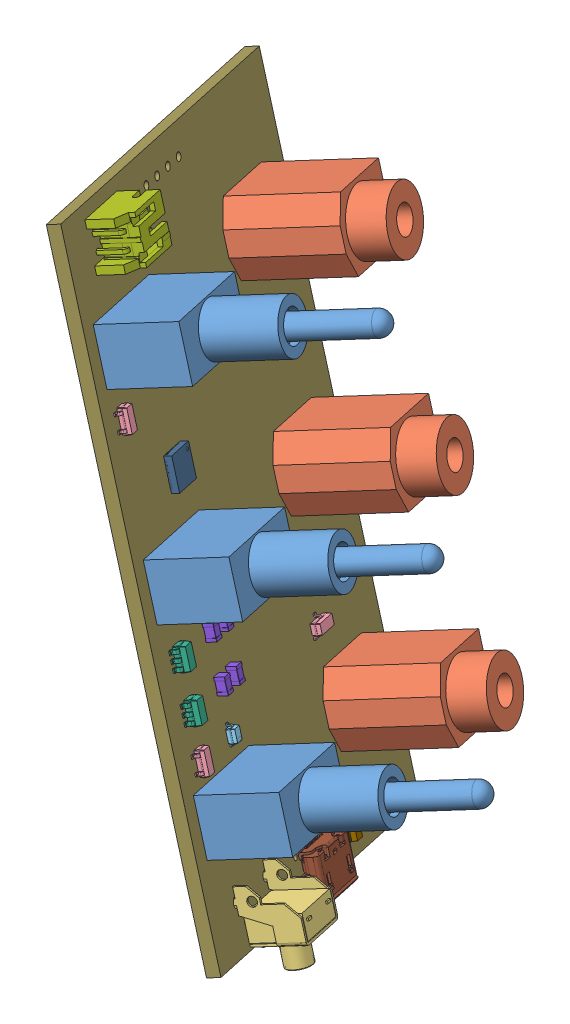
SolidWorks assembly PCB-assembly_v1.1, configuration Default. Lengths in mm.
Overall size (64.17 83.92 50.34).
100 component instances, 15 part files, 54 mates.
Components (placement in the parent):
- toggle-switch-4: toggle-switch [Default] at (-67.9927 86.0354 100.4663) x (0.334215 -0.940873 0.055309) z (0.337053 0.174117 0.925245) size (6.9 31.5 13.2)
- 3,5mmjack_MultiComp-1: 3,5mmjack_MultiComp [Default] at (-77.3391 81.8383 75.298) x (-0.334215 0.940873 -0.055309) z (0.880168 0.290588 -0.375317) size (9 10.5 21.9)
- ledTruckv1.1_new-1: ledTruckv1.1_new [Default] at (-61.225 73.4972 110.8928) x (-0.334215 0.940873 -0.055309) z (0.880168 0.290588 -0.375317) size (82.71 47 11)
  - R_0603_1608Metric-1: R_0603_1608Metric [Default] at (8.89 -22.225 1.65) x (-1 0 0) z (0 0 1) size (1.6 0.8 0.45)
    - SOLID-0-1: SOLID-0 [Default] at origin size (1.6 0.8 0.45) (hidden)
  - R_0603_1608Metric-2: R_0603_1608Metric [Default] at (8.89 -24.003 1.65) size (1.6 0.8 0.45)
    - SOLID-0-1: SOLID-0 [Default] at origin size (1.6 0.8 0.45) (hidden)
  - SW_Tactile_SPST_Angled_PTS645Vx58-2LFS-1: SW_Tactile_SPST_Angled_PTS645Vx58-2LFS [Default] at (3 -12 1.65) x (0 1 0) z (0 0 1) size (7.4 9.9 11)
    - SOLID-1-1: SOLID-1 [Default] at origin size (7.4 9.9 11)
  - R_0603_1608Metric-3: R_0603_1608Metric [Default] at (26.416 -8.636 1.65) x (-1 0 0) z (0 0 1) size (1.6 0.8 0.45)
    - SOLID-0-1: SOLID-0 [Default] at origin size (1.6 0.8 0.45) (hidden)
  - R_0603_1608Metric-4: R_0603_1608Metric [Default] at (21.082 -14.478 1.65) size (1.6 0.8 0.45)
    - SOLID-0-1: SOLID-0 [Default] at origin size (1.6 0.8 0.45) (hidden)
  - R_0603_1608Metric-5: R_0603_1608Metric [Default] at (21.082 -8.636 1.65) x (-1 0 0) z (0 0 1) size (1.6 0.8 0.45)
    - SOLID-0-1: SOLID-0 [Default] at origin size (1.6 0.8 0.45) (hidden)
  - R_0603_1608Metric-6: R_0603_1608Metric [Default] at (27.686 -35.052 1.65) x (-1 0 0) z (0 0 1) size (1.6 0.8 0.45)
    - SOLID-0-1: SOLID-0 [Default] at origin size (1.6 0.8 0.45) (hidden)
  - SOT-23-1: SOT-23 [Default] at (21.082 -4.572 1.65) x (0 -1 0) z (0 0 1) size (2.5 3 1.2)
    - SOLID-2-1: SOLID-2 [Default] at origin size (2.5 3 1.2)
  - SOT-23-2: SOT-23 [Default] at (31.496 -33.782 1.65) x (-1 0 0) z (0 0 1) size (2.5 3 1.2)
    - SOLID-2-1: SOLID-2 [Default] at origin size (2.5 3 1.2)
  - SOT-23-3: SOT-23 [Default] at (23.876 -33.782 1.65) size (2.5 3 1.2)
    - SOLID-2-1: SOLID-2 [Default] at origin size (2.5 3 1.2)
  - D_SOD-323-1: D_SOD-323 [Default] at (21.082 -11.684 1.65) size (2.5 1.25 1.1)
    - SOLID-3-1: SOLID-3 [Default] at origin size (2.5 1.25 1.1)
  - C_0603_1608Metric-1: C_0603_1608Metric [Default] at (3.81 -3.556 1.65) size (1.6 0.8 0.8)
    - SOLID-4-1: SOLID-4 [Default] at origin size (1.6 0.8 0.8) (hidden)
  - R_0603_1608Metric-7: R_0603_1608Metric [Default] at (51.938 -2.799 1.65) size (1.6 0.8 0.45)
    - SOLID-0-1: SOLID-0 [Default] at origin size (1.6 0.8 0.45) (hidden)
  - SOT-23-4: SOT-23 [Default] at (57.78 -3.688 1.65) x (0 -1 0) z (0 0 1) size (2.5 3 1.2)
    - SOLID-2-1: SOLID-2 [Default] at origin size (2.5 3 1.2)
  - C_0603_1608Metric-2: C_0603_1608Metric [Default] at (51.938 -4.45 1.65) x (-1 0 0) z (0 0 1) size (1.6 0.8 0.8)
    - SOLID-4-1: SOLID-4 [Default] at origin size (1.6 0.8 0.8) (hidden)
  - SOT-23-5-1: SOT-23-5 [Default] at (32.126 -4.704 1.65) x (0 -1 0) z (0 0 1) size (2.8 2.9 1.55)
    - SOLID-5-1: SOLID-5 [Default] at origin size (2.8 2.9 1.55)
  - SOT-23-5-2: SOT-23-5 [Default] at (26.416 -4.699 1.65) x (0 -1 0) z (0 0 1) size (2.8 2.9 1.55)
    - SOLID-5-1: SOLID-5 [Default] at origin size (2.8 2.9 1.55)
  - JST_PH_S2B-PH-K_1x02_P2.00mm_Horizontal-1: JST_PH_S2B-PH-K_1x02_P2.00mm_Horizontal [Default] at (74.544 -6.228 1.65) size (5.9 7.6 8.25)
    - SOLID-6-1: SOLID-6 [Default] at origin size (5.9 7.6 8.25)
  - R_0603_1608Metric-8: R_0603_1608Metric [Default] at (57.1958 -32.8676 1.65) x (-1 0 0) z (0 0 1) size (1.6 0.8 0.45)
    - SOLID-0-1: SOLID-0 [Default] at origin size (1.6 0.8 0.45) (hidden)
  - R_0603_1608Metric-9: R_0603_1608Metric [Default] at (57.526 -8.006 1.65) size (1.6 0.8 0.45)
    - SOLID-0-1: SOLID-0 [Default] at origin size (1.6 0.8 0.45) (hidden)
  - R_0603_1608Metric-10: R_0603_1608Metric [Default] at (57.526 -6.355 1.65) x (-1 0 0) z (0 0 1) size (1.6 0.8 0.45)
    - SOLID-0-1: SOLID-0 [Default] at origin size (1.6 0.8 0.45) (hidden)
  - R_0603_1608Metric-11: R_0603_1608Metric [Default] at (5.969 -36.068 1.65) x (0 -1 0) z (0 0 1) size (1.6 0.8 0.45)
    - SOLID-0-1: SOLID-0 [Default] at origin size (1.6 0.8 0.45) (hidden)
  - R_0603_1608Metric-12: R_0603_1608Metric [Default] at (5.9944 -31.4706 1.65) x (0 1 0) z (0 0 1) size (1.6 0.8 0.45)
    - SOLID-0-1: SOLID-0 [Default] at origin size (1.6 0.8 0.45) (hidden)
  - R_0603_1608Metric-13: R_0603_1608Metric [Default] at (46.604 -7.752 1.65) size (1.6 0.8 0.45)
    - SOLID-0-1: SOLID-0 [Default] at origin size (1.6 0.8 0.45) (hidden)
  - R_0603_1608Metric-14: R_0603_1608Metric [Default] at (59.812 -12.705 1.65) x (0 1 0) z (0 0 1) size (1.6 0.8 0.45)
    - SOLID-0-1: SOLID-0 [Default] at origin size (1.6 0.8 0.45) (hidden)
  - R_0603_1608Metric-15: R_0603_1608Metric [Default] at (32.1514 -8.636 1.65) x (-1 0 0) z (0 0 1) size (1.6 0.8 0.45)
    - SOLID-0-1: SOLID-0 [Default] at origin size (1.6 0.8 0.45) (hidden)
  - R_0603_1608Metric-16: R_0603_1608Metric [Default] at (51.938 -38.994 1.65) x (-1 0 0) z (0 0 1) size (1.6 0.8 0.45)
    - SOLID-0-1: SOLID-0 [Default] at origin size (1.6 0.8 0.45) (hidden)
  - R_0603_1608Metric-17: R_0603_1608Metric [Default] at (51.938 -34.93 1.65) size (1.6 0.8 0.45)
    - SOLID-0-1: SOLID-0 [Default] at origin size (1.6 0.8 0.45) (hidden)
  - R_0603_1608Metric-18: R_0603_1608Metric [Default] at (27.686 -36.957 1.65) size (1.6 0.8 0.45)
    - SOLID-0-1: SOLID-0 [Default] at origin size (1.6 0.8 0.45) (hidden)
  - R_0603_1608Metric-19: R_0603_1608Metric [Default] at (51.938 -36.962 1.65) x (-1 0 0) z (0 0 1) size (1.6 0.8 0.45)
    - SOLID-0-1: SOLID-0 [Default] at origin size (1.6 0.8 0.45) (hidden)
  - R_0603_1608Metric-20: R_0603_1608Metric [Default] at (51.9176 -32.9184 1.65) x (-1 0 0) z (0 0 1) size (1.6 0.8 0.45)
    - SOLID-0-1: SOLID-0 [Default] at origin size (1.6 0.8 0.45) (hidden)
  - R_0603_1608Metric-21: R_0603_1608Metric [Default] at (27.686 -38.862 1.65) size (1.6 0.8 0.45)
    - SOLID-0-1: SOLID-0 [Default] at origin size (1.6 0.8 0.45) (hidden)
  - C_0805_2012Metric-1: C_0805_2012Metric [Default] at (26.416 -14.478 1.65) x (-1 0 0) z (0 0 1) size (2 1.25 1.25)
    - SOLID-7-1: SOLID-7 [Default] at origin size (2 1.25 1.25)
  - C_0603_1608Metric-3: C_0603_1608Metric [Default] at (46.604 -6.101 1.65) x (-1 0 0) z (0 0 1) size (1.6 0.8 0.8)
    - SOLID-4-1: SOLID-4 [Default] at origin size (1.6 0.8 0.8) (hidden)
  - C_0805_2012Metric-2: C_0805_2012Metric [Default] at (32.126 -11.689 1.65) size (2 1.25 1.25)
    - SOLID-7-1: SOLID-7 [Default] at origin size (2 1.25 1.25)
  - C_0603_1608Metric-4: C_0603_1608Metric [Default] at (46.604 -4.45 1.65) size (1.6 0.8 0.8)
    - SOLID-4-1: SOLID-4 [Default] at origin size (1.6 0.8 0.8) (hidden)
  - C_0603_1608Metric-5: C_0603_1608Metric [Default] at (46.604 -2.799 1.65) size (1.6 0.8 0.8)
    - SOLID-4-1: SOLID-4 [Default] at origin size (1.6 0.8 0.8) (hidden)
  - C_0805_2012Metric-3: C_0805_2012Metric [Default] at (26.416 -11.684 1.65) x (-1 0 0) z (0 0 1) size (2 1.25 1.25)
    - SOLID-7-1: SOLID-7 [Default] at origin size (2 1.25 1.25)
  - C_0603_1608Metric-6: C_0603_1608Metric [Default] at (57.526 -9.657 1.65) size (1.6 0.8 0.8)
    - SOLID-4-1: SOLID-4 [Default] at origin size (1.6 0.8 0.8) (hidden)
  - C_0603_1608Metric-7: C_0603_1608Metric [Default] at (57.526 -15.626 1.65) size (1.6 0.8 0.8)
    - SOLID-4-1: SOLID-4 [Default] at origin size (1.6 0.8 0.8) (hidden)
  - C_0805_2012Metric-4: C_0805_2012Metric [Default] at (32.126 -14.478 1.65) size (2 1.25 1.25)
    - SOLID-7-1: SOLID-7 [Default] at origin size (2 1.25 1.25)
  - LED_0805_2012Metric-1: LED_0805_2012Metric [Default] at (2.6589 -36 1.65) x (0 -1 0) z (0 0 1) size (2 1.25 1.1)
    - SOLID-8-1: SOLID-8 [Default] at origin size (2 1.25 1.1)
  - LED_0805_2012Metric-2: LED_0805_2012Metric [Default] at (2.6589 -31.45 1.65) x (0 -1 0) z (0 0 1) size (2 1.25 1.1)
    - SOLID-8-1: SOLID-8 [Default] at origin size (2 1.25 1.1)
  - QFN-32-1EP_4x4mm_P0.4mm_EP2.65x2.65mm-1: QFN-32-1EP_4x4mm_P0.4mm_EP2.65x2.65mm [Default] at (49.136 -12.5 1.65) x (-1 0 0) z (0 0 1) size (4 4 0.92)
    - SOLID-9-1: SOLID-9 [Default] at origin size (4 4 0.92)
  - USB_Micro-B_Molex_47346-0001-1: USB_Micro-B_Molex_47346-0001 [Default] at (3.3873 -23.4924 1.65) x (0 -1 0) z (0 0 1) size (7.98 5.42 2.94)
    - SOLID-10-1: SOLID-10 [Default] at origin size (7.98 5.42 2.94)
  - Crystal_SMD_0603-4Pin_6.0x3.5mm-1: Crystal_SMD_0603-4Pin_6.0x3.5mm [Default] at (57.526 -12.705 1.65) x (0 1 0) z (0 0 1) size (6 3.5 1.03)
    - SOLID-11-1: SOLID-11 [Default] at origin size (6 3.5 1.03) (hidden)
  - COMPOUND-1: COMPOUND [Default] at origin size (80 47 1.6)
- toggle-switch-5: toggle-switch [Default] at (-76.348 109.5572 99.0835) x (0.334215 -0.940873 0.055309) z (0.337053 0.174117 0.925245) size (6.9 31.5 13.2)
- toggle-switch-6: toggle-switch [Default] at (-84.7034 133.079 97.7008) x (0.334215 -0.940873 0.055309) z (0.337053 0.174117 0.925245) size (6.9 31.5 13.2)
- 3,5mmjack_MultiComp-6: 3,5mmjack_MultiComp [Default] at (-85.6945 105.3601 73.9153) x (-0.334215 0.940873 -0.055309) z (0.880168 0.290588 -0.375317) size (9 10.5 21.9)
- 3,5mmjack_MultiComp-7: 3,5mmjack_MultiComp [Default] at (-94.0499 128.882 72.5326) x (-0.334215 0.940873 -0.055309) z (0.880168 0.290588 -0.375317) size (9 10.5 21.9)
Mates (geometry in assembly coordinates):
- Coincident1: coincident anti-aligned: plane of ledTruck_PCB.step-1/ledTruck.step-1/COMPOUND.step-1 through (-73.1659 -1.8596 36.9841) normal (0 0 1); plane of 3,5mmjack-1 through (-98.1659 -15.3596 36.9841) normal (0 0 -1)
- Coincident2: coincident anti-aligned: plane of ledTruck_PCB.step-1/ledTruck.step-1/COMPOUND.step-1 through (-100.2659 -16.2596 35.3841) normal (-1 0 0); plane of 3,5mmjack-1 through (-100.2659 -14.4596 34.9841) normal (1 0 0)
- Coincident3: coincident anti-aligned: plane of ledTruck_PCB.step-1/ledTruck.step-1/COMPOUND.step-1 through (-99.0659 -13.2596 35.3841) normal (0 1 0); plane of 3,5mmjack-1 through (-97.2659 -13.2596 34.9841) normal (0 -1 0)
- Coincident4: coincident anti-aligned: plane of ledTruck_PCB.step-1/ledTruck.step-1/COMPOUND.step-1 through (-73.1659 -1.8596 36.9841) normal (0 0 1); plane of 3,5mmjack-2 through (-73.1659 -15.3596 36.9841) normal (0 0 -1)
- Coincident5: coincident anti-aligned: plane of ledTruck_PCB.step-1/ledTruck.step-1/COMPOUND.step-1 through (-75.2659 -16.2596 35.3841) normal (-1 0 0); plane of 3,5mmjack-2 through (-75.2659 -14.4596 34.9841) normal (1 0 0)
- Coincident6: coincident anti-aligned: plane of ledTruck_PCB.step-1/ledTruck.step-1/COMPOUND.step-1 through (-73.1659 -1.8596 36.9841) normal (0 0 1); plane of 3,5mmjack-3 through (-48.1659 -15.3596 36.9841) normal (0 0 -1)
- Coincident7: coincident anti-aligned: plane of ledTruck_PCB.step-1/ledTruck.step-1/COMPOUND.step-1 through (-50.2659 -16.2596 35.3841) normal (-1 0 0); plane of 3,5mmjack-3 through (-50.2659 -14.4596 34.9841) normal (1 0 0)
- Coincident8: coincident anti-aligned: plane of ledTruck_PCB.step-1/ledTruck.step-1/COMPOUND.step-1 through (-49.0659 -13.2596 35.3841) normal (0 1 0); plane of 3,5mmjack-3 through (-47.2659 -13.2596 34.9841) normal (0 -1 0)
- Coincident12: coincident anti-aligned: plane of ledTruck_PCB.step-1/ledTruck.step-1/COMPOUND.step-1 through (-74.0659 -13.2596 35.3841) normal (0 1 0); plane of 3,5mmjack-2 through (-72.2659 -13.2596 34.9841) normal (0 -1 0)
- Coincident13: coincident anti-aligned: plane of ledTruck_PCB.step-1/ledTruck.step-1/COMPOUND.step-1 through (-73.1659 -1.8596 36.9841) normal (0 0 1); plane of toggle-switch-2 through (-18.9819 47.5049 38.7522) normal (0 0 -1)
- Coincident14: coincident anti-aligned: plane of ledTruck_PCB.step-1/ledTruck.step-1/COMPOUND.step-1 through (-47.5659 8.7904 35.3841) normal (0 -1 0); plane of toggle-switch-2 through (-19.9466 42.3912 36.5522) normal (0 1 0)
- Concentric5: concentric anti-aligned: cylinder of ledTruck_PCB.step-1/ledTruck.step-1/COMPOUND.step-1 through (-47.5659 8.1404 35.3841) axis (0 0 -1) radius 0.65; cylinder of toggle-switch-2 through (-18.7466 41.7412 36.5522) axis (0 0 1) radius 0.65
- Coincident17: coincident anti-aligned: plane of ledTruck_PCB.step-1/ledTruck.step-1/COMPOUND.step-1 through (-73.1659 -1.8596 36.9841) normal (0 0 1); plane of toggle-switch-3 through (-48.8864 61.1587 42.7227) normal (0 0 -1)
- Coincident18: coincident anti-aligned: plane of ledTruck_PCB.step-1/ledTruck.step-1/COMPOUND.step-1 through (-72.5659 8.7904 35.3841) normal (0 -1 0); plane of toggle-switch-3 through (-49.851 56.045 40.5227) normal (0 1 0)
- Concentric6: concentric anti-aligned: cylinder of ledTruck_PCB.step-1/ledTruck.step-1/COMPOUND.step-1 through (-72.5659 8.1404 35.3841) axis (0 0 -1) radius 0.65; cylinder of toggle-switch-3 through (-48.651 55.395 40.5227) axis (0 0 1) radius 0.65
- Coincident19: coincident anti-aligned: plane of ledTruck_PCB.step-1/ledTruck.step-1/COMPOUND.step-1 through (-73.1659 -1.8596 36.9841) normal (0 0 1); plane of toggle-switch-4 through (-67.9927 86.0354 100.4663) normal (-0.880168 -0.290588 0.375317)
- Coincident20: coincident anti-aligned: plane of ledTruck_PCB.step-1/ledTruck.step-1/COMPOUND.step-1 through (-97.5659 8.7904 35.3841) normal (0 -1 0); plane of toggle-switch-4 through (-68.5279 87.194 105.97) normal (-0.337053 -0.174117 -0.925245)
- Concentric7: concentric anti-aligned: cylinder of ledTruck_PCB.step-1/ledTruck.step-1/COMPOUND.step-1 through (-97.5659 8.1404 35.3841) axis (0 0 -1) radius 0.65; cylinder of toggle-switch-4 through (-67.9077 86.1782 106.6378) axis (0.880168 0.290588 -0.375317) radius 0.65
- Coincident22: coincident anti-aligned: plane of ledTruck_PCB.step-1/ledTruck.step-1/COMPOUND.step-1 through (-73.1659 -1.8596 36.9841) normal (0 0 1); plane of slideswitch-1 through (-109.6165 12.0841 36.9841) normal (0 0 -1)
- Concentric8: concentric aligned: cylinder of ledTruck_PCB.step-1/ledTruck.step-1/COMPOUND.step-1 through (-108.7259 14.6404 34.5841) axis (0 0 1) radius 0.5; cylinder of slideswitch-1 through (-108.7259 14.6404 34.7841) axis (0 0 1) radius 0.4
- Concentric9: concentric aligned: cylinder of ledTruck_PCB.step-1/ledTruck.step-1/COMPOUND.step-1 through (-108.7259 11.6404 34.5841) axis (0 0 1) radius 0.5; cylinder of slideswitch-1 through (-108.7259 11.6404 34.7841) axis (0 0 1) radius 0.4
- Coincident25: coincident anti-aligned: plane of ledTruck_PCB.step-1/ledTruck.step-1/COMPOUND.step-1 through (-73.1659 -1.8596 36.9841) normal (0 0 1); plane of 3,5mmjack_MultiComp-4 through (0.0015 35.2805 33.8495) normal (0 0 -1)
- Distance6: distance = 40 mm: cylinder of 3,5mmjack_MultiComp-4 through (-0.2008 35.1935 36.8495) axis (0 0 1) radius 1.75; plane of ledTruck_PCB.step-1/ledTruck.step-1/COMPOUND.step-1 through (-113.1659 -25.3596 35.3841) normal (-1 0 0)
- Distance7: distance = 10 mm: cylinder of 3,5mmjack_MultiComp-4 through (-0.2008 35.1935 36.8495) axis (0 0 1) radius 1.75; plane of ledTruck_PCB.step-1/ledTruck.step-1/COMPOUND.step-1 through (-33.1659 -25.3596 35.3841) normal (0 -1 0)
- Parallel2: parallel aligned: plane of ledTruck_PCB.step-1/ledTruck.step-1/COMPOUND.step-1 through (-33.1659 -25.3596 35.3841) normal (0 -1 0); plane of 3,5mmjack_MultiComp-4 through (-4.7008 29.6935 46.8495) normal (0 -1 0)
- Coincident26: coincident anti-aligned: plane of ledTruck_PCB.step-1/ledTruck.step-1/COMPOUND.step-1 through (-73.1659 -1.8596 36.9841) normal (0 0 1); plane of 3,5mmjack_MultiComp-5 through (-47.9637 -15.2725 36.9841) normal (0 0 -1)
- Distance8: distance = 65 mm: cylinder of 3,5mmjack_MultiComp-5 through (-48.1659 -15.3596 39.9841) axis (0 0 1) radius 1.75; plane of ledTruck_PCB.step-1/ledTruck.step-1/COMPOUND.step-1 through (-113.1659 -25.3596 35.3841) normal (-1 0 0)
- Distance9: distance = 10 mm: cylinder of 3,5mmjack_MultiComp-5 through (-48.1659 -15.3596 39.9841) axis (0 0 1) radius 1.75; plane of ledTruck_PCB.step-1/ledTruck.step-1/COMPOUND.step-1 through (-33.1659 -25.3596 35.3841) normal (0 -1 0)
- Parallel3: parallel aligned: plane of ledTruck_PCB.step-1/ledTruck.step-1/COMPOUND.step-1 through (-33.1659 -25.3596 35.3841) normal (0 -1 0); plane of 3,5mmjack_MultiComp-5 through (-52.6659 -20.8596 49.9841) normal (0 -1 0)
- Coincident27: coincident anti-aligned: plane of ledTruck_PCB.step-1/ledTruck.step-1/COMPOUND.step-1 through (-73.1659 -1.8596 36.9841) normal (0 0 1); plane of 3,5mmjack_MultiComp-6 through (-85.6945 105.3601 73.9153) normal (-0.880168 -0.290588 0.375317)
- Distance10: distance = 65 mm: cylinder of 3,5mmjack_MultiComp-6 through (-83.0158 106.0265 72.72) axis (0.880168 0.290588 -0.375317) radius 1.75; plane of ledTruck_PCB.step-1/ledTruck.step-1/COMPOUND.step-1 through (-113.1659 -25.3596 35.3841) normal (-1 0 0)
- Distance11: distance = 10 mm: cylinder of 3,5mmjack_MultiComp-6 through (-83.0158 106.0265 72.72) axis (0.880168 0.290588 -0.375317) radius 1.75; plane of ledTruck_PCB.step-1/ledTruck.step-1/COMPOUND.step-1 through (-33.1659 -25.3596 35.3841) normal (0 -1 0)
- Parallel4: parallel aligned: plane of ledTruck_PCB.step-1/ledTruck.step-1/COMPOUND.step-1 through (-33.1659 -25.3596 35.3841) normal (0 -1 0); plane of 3,5mmjack_MultiComp-6 through (-74.5639 103.7408 64.1268) normal (-0.337053 -0.174117 -0.925245)
- Coincident31: coincident anti-aligned: plane of toggle-switch-4 through (-67.9927 86.0354 100.4663) normal (-0.880168 -0.290588 0.375317); plane of ledTruckv1.1_new.step-1/COMPOUND.step-1 through (-81.106 107.5053 86.3367) normal (0.880168 0.290588 -0.375317)
- Coincident33: coincident anti-aligned: plane of 3,5mmjack_MultiComp-1 through (-77.3391 81.8383 75.298) normal (-0.880168 -0.290588 0.375317); plane of ledTruckv1.1_new.step-1/COMPOUND.step-1 through (-81.106 107.5053 86.3367) normal (0.880168 0.290588 -0.375317)
- Coincident37: coincident anti-aligned: plane of ledTruckv1.1_new.step-1/COMPOUND.step-1 through (-81.106 107.5053 86.3367) normal (0.880168 0.290588 -0.375317); plane of toggle-switch-5 through (-76.348 109.5572 99.0835) normal (-0.880168 -0.290588 0.375317)
- Coincident40: coincident anti-aligned: plane of ledTruckv1.1_new.step-1/COMPOUND.step-1 through (-81.106 107.5053 86.3367) normal (0.880168 0.290588 -0.375317); plane of toggle-switch-6 through (-84.7034 133.079 97.7008) normal (-0.880168 -0.290588 0.375317)
- Coincident44: coincident anti-aligned: plane of ledTruckv1.1_new.step-1/COMPOUND.step-1 through (-81.106 107.5053 86.3367) normal (0.880168 0.290588 -0.375317); plane of 3,5mmjack_MultiComp-6 through (-85.6945 105.3601 73.9153) normal (-0.880168 -0.290588 0.375317)
- Coincident47: coincident anti-aligned: plane of ledTruckv1.1_new.step-1/COMPOUND.step-1 through (-81.106 107.5053 86.3367) normal (0.880168 0.290588 -0.375317); plane of 3,5mmjack_MultiComp-7 through (-94.0499 128.882 72.5326) normal (-0.880168 -0.290588 0.375317)
- Distance12: distance = 15 mm: cylinder of 3,5mmjack_MultiComp-1 through (-74.6604 82.5046 74.1027) axis (0.880168 0.290588 -0.375317) radius 1.75; line of ledTruckv1.1_new.step-1/COMPOUND.step-1 through (-75.6582 65.7786 66.8058) axis (0.337053 0.174117 0.925245)
- Distance13: distance = 37 mm: cylinder of 3,5mmjack_MultiComp-1 through (-74.6604 82.5046 74.1027) axis (0.880168 0.290588 -0.375317) radius 1.75; line of ledTruckv1.1_new.step-1/COMPOUND.step-1 through (-59.8167 73.9621 110.2923) axis (-0.334215 0.940873 -0.055309)
- Parallel8: parallel aligned: plane of 3,5mmjack_MultiComp-1 through (-66.2085 80.219 65.5096) normal (-0.337053 -0.174117 -0.925245); plane of ledTruckv1.1_new.step-1/COMPOUND.step-1 through (-103.8036 140.5835 62.9816) normal (-0.337053 -0.174117 -0.925245)
- Distance14: distance = 40 mm: cylinder of 3,5mmjack_MultiComp-6 through (-83.0158 106.0265 72.72) axis (0.880168 0.290588 -0.375317) radius 1.75; line of ledTruckv1.1_new.step-1/COMPOUND.step-1 through (-75.6582 65.7786 66.8058) axis (0.337053 0.174117 0.925245)
- Distance15: distance = 37 mm: cylinder of 3,5mmjack_MultiComp-6 through (-83.0158 106.0265 72.72) axis (0.880168 0.290588 -0.375317) radius 1.75; line of ledTruckv1.1_new.step-1/COMPOUND.step-1 through (-59.8167 73.9621 110.2923) axis (-0.334215 0.940873 -0.055309)
- Parallel11: parallel aligned: plane of ledTruckv1.1_new.step-1/COMPOUND.step-1 through (-103.8036 140.5835 62.9816) normal (-0.337053 -0.174117 -0.925245); plane of 3,5mmjack_MultiComp-6 through (-74.5639 103.7408 64.1268) normal (-0.337053 -0.174117 -0.925245)
- Distance16: distance = 65 mm: cylinder of 3,5mmjack_MultiComp-7 through (-91.3711 129.5483 71.3373) axis (0.880168 0.290588 -0.375317) radius 1.75; line of ledTruckv1.1_new.step-1/COMPOUND.step-1 through (-75.6582 65.7786 66.8058) axis (0.337053 0.174117 0.925245)
- Distance17: distance = 37 mm: cylinder of 3,5mmjack_MultiComp-7 through (-91.3711 129.5483 71.3373) axis (0.880168 0.290588 -0.375317) radius 1.75; line of ledTruckv1.1_new.step-1/COMPOUND.step-1 through (-59.8167 73.9621 110.2923) axis (-0.334215 0.940873 -0.055309)
- Parallel14: parallel aligned: plane of ledTruckv1.1_new.step-1/COMPOUND.step-1 through (-103.8036 140.5835 62.9816) normal (-0.337053 -0.174117 -0.925245); plane of 3,5mmjack_MultiComp-7 through (-82.9193 127.2626 62.7441) normal (-0.337053 -0.174117 -0.925245)
- Distance18: distance = 15 mm: cylinder of toggle-switch-4 through (-51.6889 91.8608 94.4523) axis (-0.880168 -0.290588 0.375317) radius 3.25; line of ledTruckv1.1_new.step-1/COMPOUND.step-1 through (-75.6582 65.7786 66.8058) axis (0.337053 0.174117 0.925245)
- Distance19: distance = 40 mm: cylinder of toggle-switch-5 through (-60.0443 115.3826 93.0695) axis (-0.880168 -0.290588 0.375317) radius 3.25; line of ledTruckv1.1_new.step-1/COMPOUND.step-1 through (-75.6582 65.7786 66.8058) axis (0.337053 0.174117 0.925245)
- Distance20: distance = 65 mm: cylinder of toggle-switch-6 through (-68.3996 138.9044 91.6868) axis (-0.880168 -0.290588 0.375317) radius 3.25; line of ledTruckv1.1_new.step-1/COMPOUND.step-1 through (-75.6582 65.7786 66.8058) axis (0.337053 0.174117 0.925245)
- Distance21: distance = 8.8 mm: cylinder of toggle-switch-4 through (-51.6889 91.8608 94.4523) axis (-0.880168 -0.290588 0.375317) radius 3.25; line of ledTruckv1.1_new.step-1/COMPOUND.step-1 through (-59.8167 73.9621 110.2923) axis (-0.334215 0.940873 -0.055309)
- Distance22: distance = 8.8 mm: cylinder of toggle-switch-5 through (-60.0443 115.3826 93.0695) axis (-0.880168 -0.290588 0.375317) radius 3.25; line of ledTruckv1.1_new.step-1/COMPOUND.step-1 through (-59.8167 73.9621 110.2923) axis (-0.334215 0.940873 -0.055309)
- Distance23: distance = 8.8 mm: cylinder of toggle-switch-6 through (-68.3996 138.9044 91.6868) axis (-0.880168 -0.290588 0.375317) radius 3.25; line of ledTruckv1.1_new.step-1/COMPOUND.step-1 through (-59.8167 73.9621 110.2923) axis (-0.334215 0.940873 -0.055309)
